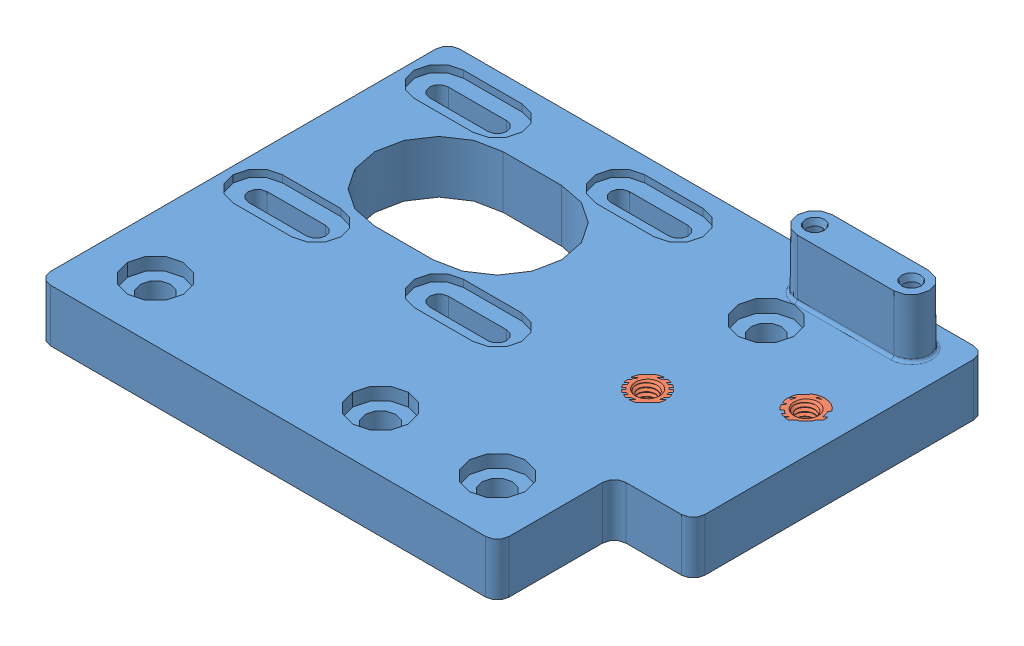
SolidWorks assembly right_motor_plate_with_inserts, configuration Default. Lengths in mm.
Overall size (92 19.4 70).
3 component instances, 2 part files, 4 mates.
Components (placement in the parent):
- motor_corner_bracket-1: motor_corner_bracket [Right Motor Corner Bracket] at (197.071 392.0105 15.3157) size (92 19.4 70)
- m4_heat_set_insert_long_94180A353-1: m4_heat_set_insert_long_94180A353 [94180A353] at (360.571 401.0105 -31.0093) size (6.35 8.38 6.35)
- m4_heat_set_insert_long_94180A353-2: m4_heat_set_insert_long_94180A353 [94180A353] at (344.071 401.0105 -20.3843) size (6.35 8.38 6.35)
Mates (geometry in assembly coordinates):
- Coincident1594070890: coincident aligned: plane of motor_corner_bracket-1 through (354.071 401.0105 15.3157) normal (0 1 0); plane of m4_heat_set_insert_long_94180A353-1 through (360.571 401.0105 -31.0093) normal (0 1 0)
- Coincident1594070891: coincident aligned: plane of motor_corner_bracket-1 through (354.071 401.0105 15.3157) normal (0 1 0); plane of m4_heat_set_insert_long_94180A353-2 through (344.071 401.0105 -20.3843) normal (0 1 0)
- Concentric754010296: concentric anti-aligned: cylinder of motor_corner_bracket-1 through (360.571 401.0105 -31.0093) axis (0 -1 0) radius 2.7; unknown of m4_heat_set_insert_long_94180A353-1
- Concentric754010297: concentric anti-aligned: cylinder of motor_corner_bracket-1 through (344.071 401.0105 -20.3843) axis (0 -1 0) radius 2.7; unknown of m4_heat_set_insert_long_94180A353-2
